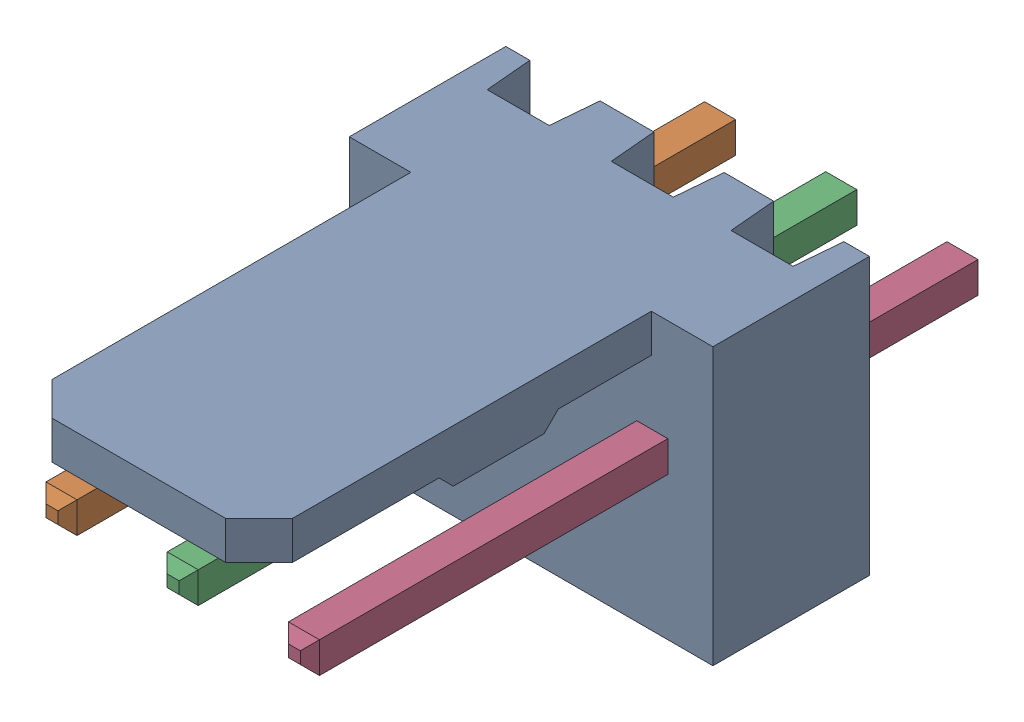
SolidWorks assembly Molex PCB 3 pin v2 v6_3, configuration Default. Lengths in mm.
Overall size (7.62 5.79 14.92).
4 component instances, 2 part files, 0 mates.
Components (placement in the parent):
- BASE9710016_2-1: BASE9710016_2 [Default] at (2.54 2.895 -8.22) size (7.62 5.79 11.5)
- PINO9710016_2-1: PINO9710016_2 [Default] at (1.27 3.325 -0.72) size (0.65 0.65 14.2)
- PINO9710016_2-2: PINO9710016_2 [Default] at (3.81 3.325 -0.72) size (0.65 0.65 14.2)
- PINO9710016_2-3: PINO9710016_2 [Default] at (6.35 3.325 -0.72) size (0.65 0.65 14.2)
